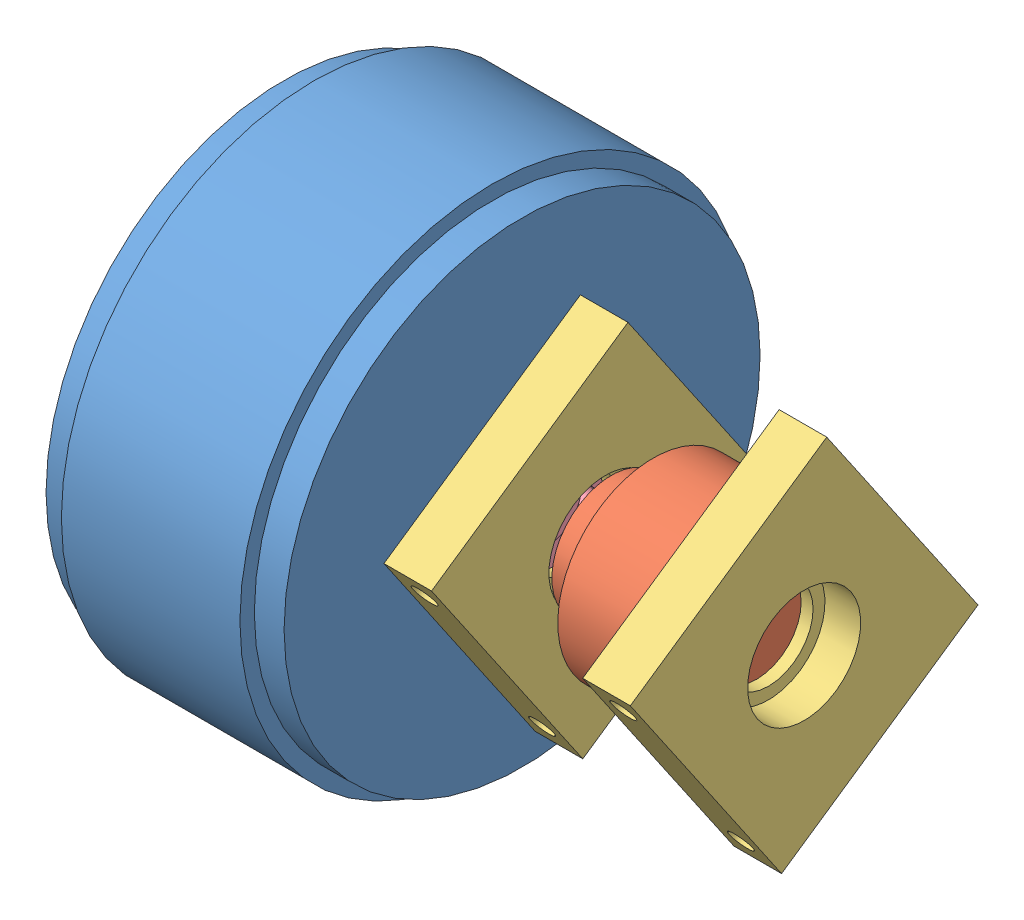
SolidWorks assembly ASSEMB TAMB+SUPPORT, configuration Default. Lengths in mm.
Overall size (105.04 84.84 84.84).
5 component instances, 4 part files, 10 mates.
Components (placement in the parent):
- Tombour-1: Tombour [Défaut] at (-5.9119 -3.3103 11.7008) size (103.56 84.84 84.84)
- small_roue-1: small_roue [Défaut] at (30.7881 -3.3103 11.7008) x (0 0.220321 0.975427) z (-1 0 0) size (32 32 20.4)
- support_roulement-1: support_roulement [Défaut] at (8.0881 -3.3103 11.7008) x (0 -0.825204 -0.564835) z (1 0 0) size (45 40 8)
- accouplement moteur-1: accouplement moteur [Défaut] at (-2.9119 -3.3103 11.7008) x (1 0 0) z (0 -0.999313 -0.037067) size (9 25 25)
- support_roulement-2: support_roulement [Défaut] at (41.4881 -3.3103 11.7008) x (0 -0.825204 -0.564835) z (1 0 0) size (45 40 8)
Mates (geometry in assembly coordinates):
- Concentric1: concentric anti-aligned: cylinder of Tombour-1 through (-5.9119 -3.3103 11.7008) axis (-1 0 0) radius 12.5; cylinder of support_roulement-1 through (8.0881 -3.3103 11.7008) axis (1 0 0) radius 7.5
- Coincident1: coincident anti-aligned: plane of Tombour-1 through (-2.9119 9.1897 11.7008) normal (1 0 0); plane of accouplement moteur-1 through (-2.9119 -3.4215 14.6988) normal (-1 0 0)
- Parallel1: parallel anti-aligned: plane of Tombour-1 through (2.0881 36.6897 11.7008) normal (1 0 0); plane of support_roulement-1 through (8.0881 -3.3103 11.7008) normal (-1 0 0)
- Coincident2: coincident aligned: plane of support_roulement-1 through (16.0881 26.5535 7.9056) normal (0 0.564835 -0.825204); plane of support_roulement-2 through (49.4881 26.5535 7.9056) normal (0 0.564835 -0.825204)
- Coincident3: coincident aligned: plane of support_roulement-1 through (16.0881 -33.1741 15.4961) normal (0 -0.825204 -0.564835); plane of support_roulement-2 through (49.4881 -33.1741 15.4961) normal (0 -0.825204 -0.564835)
- Distance1: distance = 25.4 mm anti-aligned: plane of support_roulement-2 through (41.4881 -3.3103 11.7008) normal (-1 0 0); plane of support_roulement-1 through (16.0881 -3.3103 11.7008) normal (1 0 0)
- Distance3: distance = 2 mm anti-aligned: plane of accouplement moteur-1 through (6.0881 -3.5327 17.6967) normal (1 0 0); plane of support_roulement-1 through (8.0881 -3.3103 11.7008) normal (-1 0 0)
- Distance4: distance = 1 mm anti-aligned: plane of support_roulement-1 through (16.0881 -3.3103 11.7008) normal (1 0 0); plane of small_roue-1 through (17.0881 -3.3103 11.7008) normal (-1 0 0)
- Concentric5: concentric aligned: cylinder of small_roue-1 through (17.0881 -3.3103 11.7008) axis (1 0 0) radius 3.025; cylinder of support_roulement-1 through (10.0881 -3.3103 11.7008) axis (1 0 0) radius 9.5
- Concentric6: concentric aligned: cylinder of Tombour-1 through (-5.9119 -3.3103 11.7008) axis (-1 0 0) radius 12.5; cylinder of accouplement moteur-1 through (-2.9119 -3.3103 11.7008) axis (-1 0 0) radius 12.5
